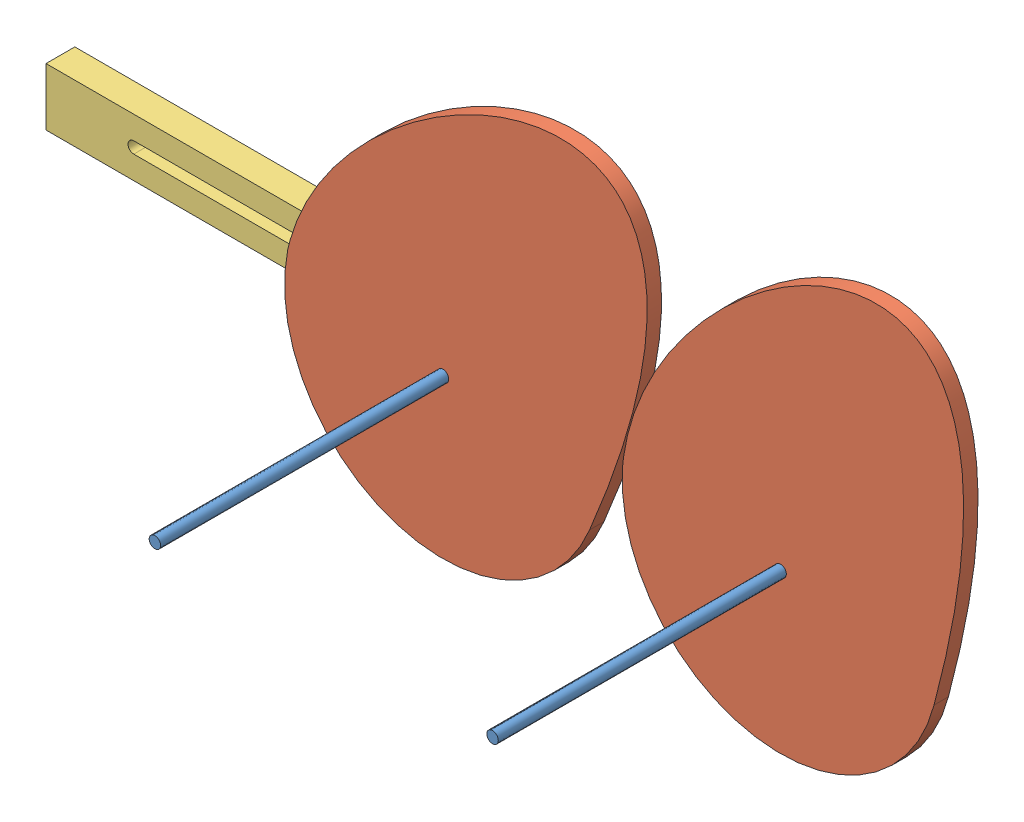
SolidWorks assembly two-spoke-test, configuration Default. Lengths in mm.
Overall size (352.7 201.06 150).
5 component instances, 3 part files, 10 mates.
Components (placement in the parent):
- shell-spoke-1: shell-spoke [Default] at origin size (4 4 150)
- shell-mockup-1: shell-mockup [Default] at (0 0 -5) x (0.968338 -0.249642 0) z (0 0 1) size (116.49 169.53 5)
- mock-spoke-slider-1: mock-spoke-slider [Default] at (-70 0 -15) x (-1 0 0) z (0 0 -1) size (300 20 10)
- shell-spoke-2: shell-spoke [Default] at (-117.1978 0 0) x (0.367287 -0.930107 0) z (0 0 1) size (4 4 150)
- shell-mockup-2: shell-mockup [Default] at (-117.1978 0 -5) x (0.925176 -0.379539 0) z (0 0 1) size (116.49 169.53 5)
Mates (geometry in assembly coordinates):
- Coincident1: coordinate: point of shell-spoke-1
- Concentric1: concentric anti-aligned: cylinder of shell-spoke-1 through (0 0 -50) axis (0 0 1) radius 2; cylinder of shell-mockup-1 through (0 0 0) axis (0 0 -1) radius 2
- Coincident2: coincident aligned: plane of shell-mockup-1 through (0 0 0) normal (0 0 1)
- Concentric2: concentric aligned: cylinder of shell-spoke-1 through (0 0 -50) axis (0 0 1) radius 2; cylinder of mock-spoke-slider-1 through (0 0 -25) axis (0 0 1) radius 2
- Distance1: distance = 10 mm anti-aligned: plane of shell-mockup-1 through (0 0 -5) normal (0 0 -1); plane of mock-spoke-slider-1 through (-70 0 -15) normal (0 0 1)
- Parallel1: parallel aligned: plane of mock-spoke-slider-1 through (30 10 -25) normal (0 1 0)
- Slot1: slot aligned: cylinder of shell-spoke-2 through (-117.1978 0 -50) axis (0 0 1) radius 2; plane of mock-spoke-slider-1 through (-70 -2 -25) normal (0 1 0); cylinder of mock-spoke-slider-1 through (-70 0 -25) axis (0 0 1) radius 2
- Coincident4: coincident aligned: plane of shell-spoke-1 through (0 0 -50) normal (0 0 -1); plane of shell-spoke-2 through (-117.1978 0 -50) normal (0 0 -1)
- Concentric3: concentric anti-aligned: cylinder of shell-spoke-2 through (-117.1978 0 -50) axis (0 0 1) radius 2; cylinder of shell-mockup-2 through (-117.1978 0 0) axis (0 0 -1) radius 2
- Coincident6: coincident aligned: plane of shell-mockup-1 through (0 0 -5) normal (0 0 -1); plane of shell-mockup-2 through (-117.1978 0 -5) normal (0 0 -1)
